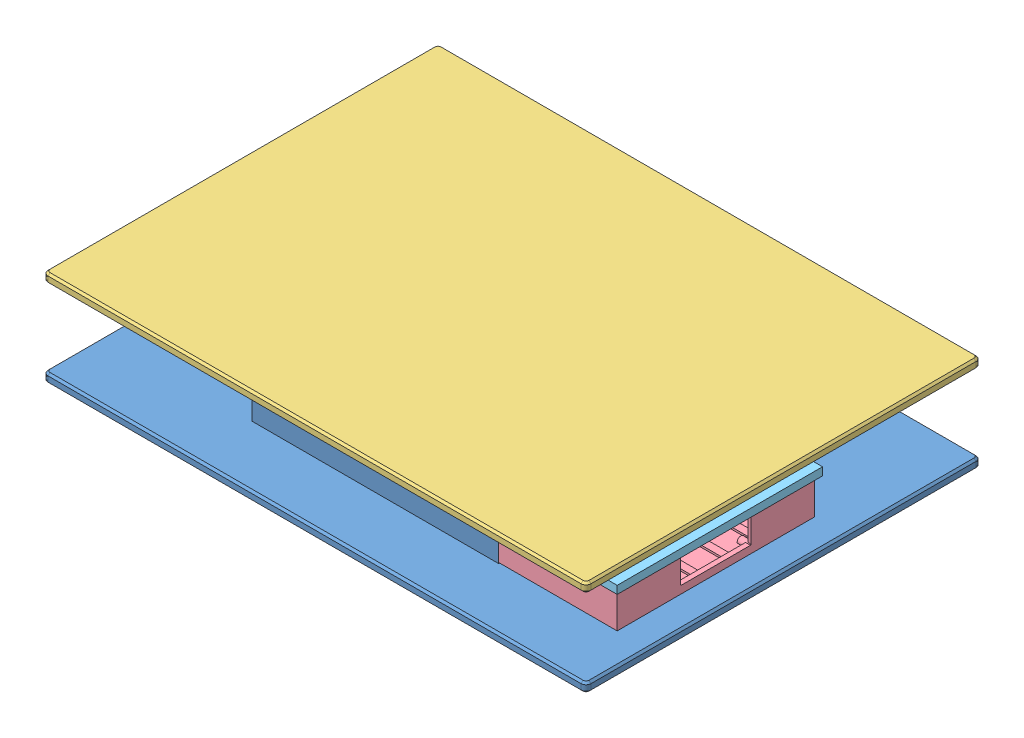
SolidWorks assembly Assembly 05-09-2017, configuration Default. Lengths in mm.
Overall size (550 97.15 400).
5 component instances, 5 part files, 12 mates.
Components (placement in the parent):
- Placa base 05-09-2017-1: Placa base 05-09-2017 [Default] at (195.8199 251.6079 441.5265) size (550 28.57 400)
- Sensor 05-09-2017-1: Sensor 05-09-2017 [Predeterminado] at (208.5199 300.1829 500.8765) x (0 0 1) z (0 -1 0) size (150 25.4 40)
- Placa Tara 05-09-2017-1: Placa Tara 05-09-2017 [Default] at (195.8199 348.7579 441.5265) x (-1 0 0) z (0 0 1) size (550 28.57 400)
- Caja de circuitos 05-09-2017-1: Caja de circuitos 05-09-2017 [Predeterminado] at (380.8199 262.1329 479.9765) x (0 0 -1) z (1 0 0) size (200 41 120)
- Tapa de circuitos 05-09-2017-1: Tapa de circuitos 05-09-2017 [Predeterminado] at (380.8199 298.1329 479.9765) x (0 0 -1) z (1 0 0) size (208 24 128)
Mates (geometry in assembly coordinates):
- Concentric2: concentric aligned: cylinder of Placa base 05-09-2017-1 through (195.8199 280.1829 550.6765) axis (0 -1 0) radius 3; cylinder of Sensor 05-09-2017-1 through (195.8199 296.1829 550.6765) axis (0 -1 0) radius 2.75
- Concentric3: concentric aligned: cylinder of Placa base 05-09-2017-1 through (195.8199 280.1829 569.7765) axis (0 -1 0) radius 3; cylinder of Sensor 05-09-2017-1 through (195.8199 296.1829 569.7765) axis (0 -1 0) radius 2.75
- Coincident1: coincident anti-aligned: plane of Placa base 05-09-2017-1 through (195.8199 280.1829 441.5265) normal (0 1 0); plane of Sensor 05-09-2017-1 through (183.1199 280.1829 425.8765) normal (0 -1 0)
- Concentric4: concentric: cylinder of Sensor 05-09-2017-1 through (195.8199 304.1829 451.0765) axis (0 1 0) radius 2.75; cylinder of Placa Tara 05-09-2017-1 through (195.8199 320.1829 451.0765) axis (0 1 0) radius 3
- Concentric5: concentric: cylinder of Sensor 05-09-2017-1 through (195.8199 304.1829 431.9765) axis (0 1 0) radius 2.75; cylinder of Placa Tara 05-09-2017-1 through (195.8199 320.1829 431.9765) axis (0 1 0) radius 3
- Coincident2: coincident anti-aligned: plane of Sensor 05-09-2017-1 through (183.1199 320.1829 425.8765) normal (0 1 0); plane of Placa Tara 05-09-2017-1 through (195.8199 320.1829 441.5265) normal (0 -1 0)
- Concentric6: concentric aligned: cylinder of Caja de circuitos 05-09-2017-1 through (430.8199 293.8278 389.9765) axis (0 1 0) radius 2.5; cylinder of Tapa de circuitos 05-09-2017-1 through (430.8199 293.8278 389.9765) axis (0 1 0) radius 2.5
- Concentric7: concentric aligned: cylinder of Caja de circuitos 05-09-2017-1 through (330.8199 293.8278 569.9765) axis (0 1 0) radius 2.5; cylinder of Tapa de circuitos 05-09-2017-1 through (330.8199 293.8278 569.9765) axis (0 1 0) radius 2.5
- Coincident3: coincident anti-aligned: plane of Caja de circuitos 05-09-2017-1 through (380.8199 313.8278 479.9765) normal (0 1 0); plane of Tapa de circuitos 05-09-2017-1 through (380.8199 313.8278 479.9765) normal (0 -1 0)
- Coincident4: coincident anti-aligned: plane of Placa base 05-09-2017-1 through (320.8199 280.1829 541.8765) normal (1 0 0); plane of Caja de circuitos 05-09-2017-1 through (320.8199 302.1329 579.9765) normal (-1 0 0)
- Coincident5: coincident aligned: plane of Placa base 05-09-2017-1 through (70.8199 280.1829 579.9765) normal (0 0 1); plane of Caja de circuitos 05-09-2017-1 through (320.8199 302.1329 579.9765) normal (0 0 1)
- Coincident6: coincident anti-aligned: plane of Placa base 05-09-2017-1 through (195.8199 261.1329 441.5265) normal (0 1 0); plane of Caja de circuitos 05-09-2017-1 through (380.8199 261.1329 479.9765) normal (0 -1 0)
